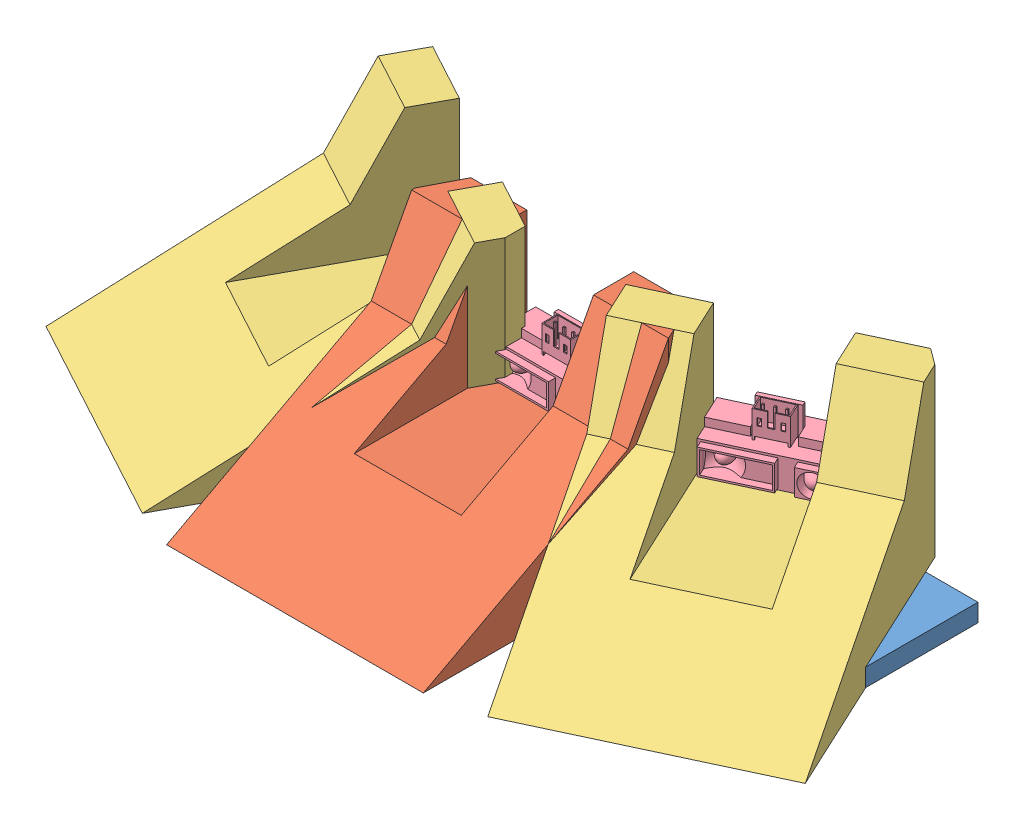
SolidWorks assembly Ensamble_Frente_Alvaro, configuration Predeterminado. Lengths in mm.
Overall size (217.46 51.82 106.47).
7 component instances, 4 part files, 21 mates.
Components (placement in the parent):
- Base_Frente-1: Base_Frente [Predeterminado] at (-15.8721 38.8772 167.2685) size (186 5 59.82)
- Frente_Centro_Acero-1: Frente_Centro_Acero [Predeterminado] at (16.4053 38.8772 154.5839) x (-1 0 0) z (0 0 -1) size (72 51.82 80)
- Frente_Laterales_Aceros-1: Frente_Laterales_Aceros [Predeterminado] at (-87.4468 38.8772 128.1119) x (-0.476117 0 0.879382) z (-0.879382 0 -0.476117) size (80 51.82 67)
- Frente_Laterales_Aceros-2: Frente_Laterales_Aceros [Predeterminado] at (-2.6125 38.8772 158.8001) x (0.422618 0 0.906308) z (-0.906308 0 0.422618) size (80 51.82 67)
- Sharp-2: Sharp [Default] at (-19.3447 59.8972 152.5839) x (-1 0 0) z (0 0 1) size (44.5 18.9 13.5)
- Sharp-4: Sharp [Default] at (26.677 59.8972 142.9354) x (-0.906308 0 0.422618) z (0.422618 0 0.906308) size (44.5 18.9 13.5)
- Sharp-5: Sharp [Default] at (-57.2551 59.8972 142.184) x (-0.879382 0 -0.476117) z (-0.476117 0 0.879382) size (44.5 18.9 13.5)
Mates (geometry in assembly coordinates):
- Paralelo1: parallel: plane of Base_Frente-1 through (-49.9535 43.8772 199.5839) normal (0 0 1); plane of Frente_Centro_Acero-1 through (16.4063 38.8772 199.5839) normal (0 0 -1)
- Paralelo2: parallel: plane of Base_Frente-1 through (-49.9535 43.8772 199.5839) normal (-0.476117 0 0.879382); plane of Frente_Laterales_Aceros-1 through (-49.9526 38.8772 199.5844) normal (0.476117 0 -0.879382)
- Coincidente4: coincident: line of Base_Frente-1 through (16.4053 43.8772 199.5839) axis (0 -1 0); line of Frente_Centro_Acero-1 through (16.4053 38.8772 199.5839) axis (0 1 0)
- Coincidente5: coincident: plane of Base_Frente-1 through (-15.8721 43.8772 167.2685) normal (0 1 0); plane of Frente_Centro_Acero-1 through (16.4063 43.8772 154.5839) normal (0 -1 0)
- Coincidente6: coincident: line of Base_Frente-1 through (-108.8721 43.8772 167.6841) axis (0 -1 0); line of Frente_Laterales_Aceros-1 through (-108.8721 38.8772 167.6841) axis (0 1 0)
- Coincidente7: coincident: plane of Base_Frente-1 through (-15.8721 43.8772 167.2685) normal (0 1 0); plane of Frente_Laterales_Aceros-1 through (-28.5274 43.8772 160.0122) normal (0 -1 0)
- Paralelo3: parallel: plane of Base_Frente-1 through (16.4053 43.8772 199.5839) normal (0.422618 0 0.906308); plane of Frente_Laterales_Aceros-2 through (77.1288 38.8772 171.2681) normal (-0.422618 0 -0.906308)
- Coincidente9: coincident: line of Base_Frente-1 through (77.1279 43.8772 171.2685) axis (0 -1 0); line of Frente_Laterales_Aceros-2 through (77.1279 43.8772 171.2685) axis (0 -1 0)
- Coincidente10: coincident: plane of Base_Frente-1 through (-15.8721 43.8772 167.2685) normal (0 1 0); plane of Frente_Laterales_Aceros-2 through (58.111 43.8772 130.4842) normal (0 -1 0)
- Paralelo4: parallel: plane of Frente_Centro_Acero-1 through (-55.5947 38.8772 154.5839) normal (0 0 -1); plane of Sharp-2 through (-0.8447 59.8972 152.5839) normal (0 0 -1)
- Coincidente12: coincident: plane of Frente_Centro_Acero-1 through (-4.5947 55.6972 154.5839) normal (-1 0 0); plane of Sharp-2 through (-4.5947 66.3972 166.0839) normal (1 0 0)
- Coincidente13: coincident: plane of Frente_Centro_Acero-1 through (16.4053 55.6972 154.5839) normal (0 1 0); plane of Sharp-2 through (-4.5947 55.6972 166.0839) normal (0 -1 0)
- Coincidente14: coincident: plane of Frente_Centro_Acero-1 through (-55.5947 38.8772 154.5839) normal (0 0 -1); plane of Sharp-2 through (-37.8447 59.8972 154.5839) normal (0 0 1)
- Paralelo5: parallel: plane of Frente_Laterales_Aceros-1 through (-87.4468 38.8772 128.1119) normal (0.476117 0 -0.879382); plane of Sharp-5 through (-40.9866 59.8972 150.9922) normal (0.476117 0 -0.879382)
- Coincidente16: coincident: plane of Frente_Laterales_Aceros-1 through (-87.4468 55.6972 128.1119) normal (0 1 0); plane of Sharp-5 through (-50.7118 55.6972 161.0784) normal (0 -1 0)
- Coincidente17: coincident: plane of Frente_Laterales_Aceros-1 through (-71.1783 55.6972 136.9201) normal (0.879382 0 0.476117); plane of Sharp-5 through (-76.6536 66.3972 147.033) normal (-0.879382 0 -0.476117)
- Coincidente18: coincident: plane of Frente_Laterales_Aceros-1 through (-87.4468 38.8772 128.1119) normal (0.476117 0 -0.879382); plane of Sharp-5 through (-74.4759 59.8972 135.1346) normal (-0.476117 0 0.879382)
- Paralelo6: parallel: plane of Frente_Laterales_Aceros-2 through (-2.6125 38.8772 158.8001) normal (-0.422618 0 -0.906308); plane of Sharp-4 through (43.4437 59.8972 135.117) normal (-0.422618 0 -0.906308)
- Coincidente20: coincident: plane of Frente_Laterales_Aceros-2 through (-2.6125 55.6972 158.8001) normal (0 1 0); plane of Sharp-4 through (45.7503 55.6972 148.9369) normal (0 -1 0)
- Coincidente21: coincident: plane of Frente_Laterales_Aceros-2 through (14.1542 55.6972 150.9816) normal (0.906308 0 -0.422618); plane of Sharp-4 through (19.0143 66.3972 161.4042) normal (-0.906308 0 0.422618)
- Coincidente22: coincident: plane of Frente_Laterales_Aceros-2 through (-2.6125 38.8772 158.8001) normal (-0.422618 0 -0.906308); plane of Sharp-4 through (44.2889 59.8972 136.9296) normal (0.422618 0 0.906308)
